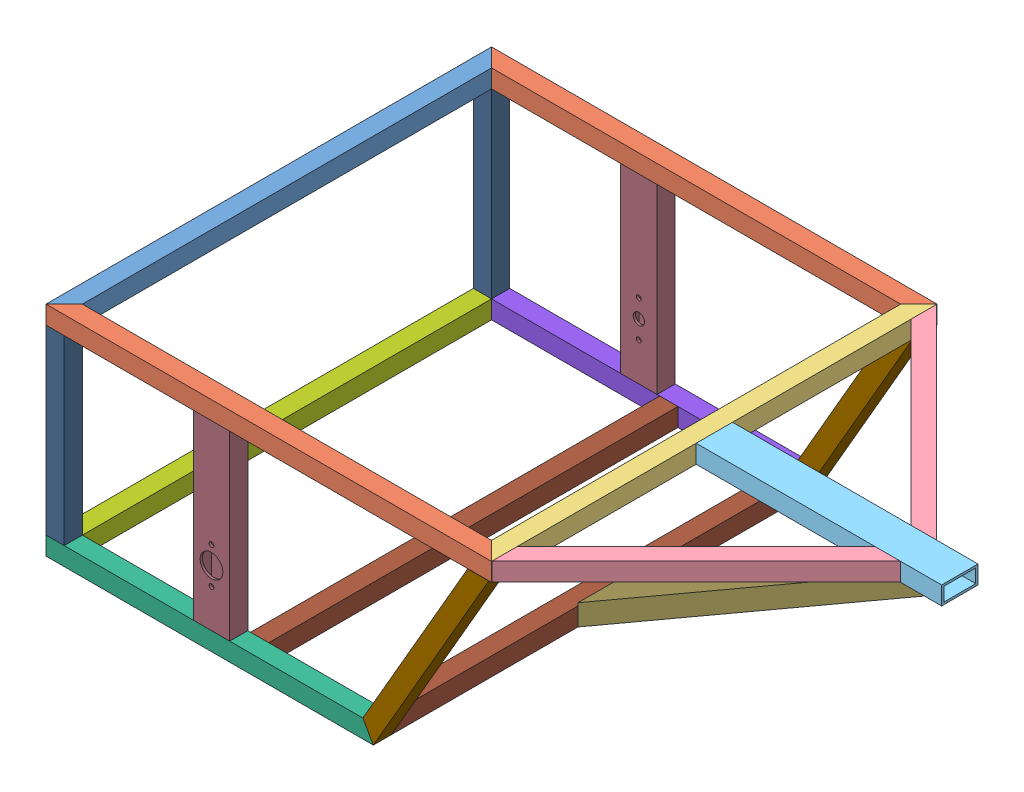
SolidWorks assembly chassis weldment, configuration Default. Lengths in mm.
Overall size (965.2 304.8 622.3).
21 component instances, 13 part files, 0 mates.
Components (placement in the parent):
- chassis weldment top-1-1: chassis weldment top-1 [Default] at (64.6916 38.689 -16.8871) size (965.2 25.4 622.3)
  - frame member front-11-1: frame member front-11 [Default] at origin size (25.4 25.4 622.3)
  - frame member side-11-1: frame member side-11 [Default] at (298.45 0 298.45) x (0 0 1) z (-1 0 0) size (25.4 25.4 622.3)
  - frame member side-11-2: frame member side-11 [Default] at (298.45 0 -298.45) x (0 0 -1) z (-1 0 0) size (25.4 25.4 622.3)
  - frame member crossbrace middle-11-1: frame member crossbrace middle-11 [Default] at (596.9 0 0) x (-1 0 0) z (0 0 1) size (25.4 25.4 622.3)
  - frame member back angle-11-1: frame member back angle-11 [Default] at (743.1813 0 -158.9813) x (-0.707107 0 0.707107) z (-0.707107 0 -0.707107) size (25.4 25.4 403.23)
  - frame member back angle-11-2: frame member back angle-11 [Default] at (743.1813 0 158.9813) x (-0.707107 0 -0.707107) z (-0.707107 0 0.707107) size (25.4 25.4 403.23)
  - frame member back center-11-1: frame member back center-11 [Default] at (781.05 0 0) x (0 0 -1) z (1 0 0) size (50.8 25.4 342.9)
- chassis weldment bottom-1-1: chassis weldment bottom-1 [Default] at (280.5916 -240.711 281.5629) x (0 -1 0) z (-1 0 0) size (301.4 622.3 941.13)
  - bottom frame member side-1-1: bottom frame member side-1 [Default] at origin size (25.4 25.4 457.2)
  - bottom frame member crossbrace-1-1: bottom frame member crossbrace-1 [Default] at (0 -298.45 215.9) x (0 0 -1) z (0 1 0) size (25.4 25.4 622.3)
  - bottom frame member side_MIR-1-1: bottom frame member side_MIR-1 [Default] at (0 -596.9 0) x (1 0 0) z (0 0 -1) size (25.4 25.4 457.2)
  - bottom frame member angle-1-1: bottom frame member angle-1 [Default] at (-133.1938 -596.9 -298.1671) x (0.5 0 -0.866025) z (0.866025 0 0.5) size (25.4 25.4 322.26)
  - bottom frame member angle-1-2: bottom frame member angle-1 [Default] at (-133.1938 0 -298.1671) x (0.5 0 -0.866025) z (0.866025 0 0.5) size (25.4 25.4 322.26)
  - bottom frame member back upright-1-1: bottom frame member back upright-1 [Default] at (-139.7 -596.9 215.9) x (0 0 -1) z (1 0 0) size (25.4 25.4 254)
  - bottom frame member back upright-1-2: bottom frame member back upright-1 [Default] at (-139.7 0 215.9) x (0 0 -1) z (1 0 0) size (25.4 25.4 254)
  - bottom frame member crossbrace back-1-1: bottom frame member crossbrace back-1 [Default] at (0 -298.45 -215.9) x (1 0 0) z (0 -1 0) size (25.4 25.4 571.5)
  - bottom frame member brace-1-1: bottom frame member brace-1 [Default] at (-137.9985 -298.45 -464.2175) x (0 1 0) z (0.5 0 0.866025) size (50.8 25.4 558.8)
  - bottom frame member crossbrace back-1-2: bottom frame member crossbrace back-1 [Default] at (0 -298.45 -44.45) x (1 0 0) z (0 1 0) size (25.4 25.4 571.5)
  - wheel mount vertical-1-1: wheel mount vertical-1 [Default] at (-139.7 -596.9 -2.54) x (0 0 1) z (1 0 0) size (50.8 25.4 254)
  - wheel mount vertical-1-2: wheel mount vertical-1 [Default] at (-139.7 0 -2.54) x (0 0 -1) z (1 0 0) size (50.8 25.4 254)
